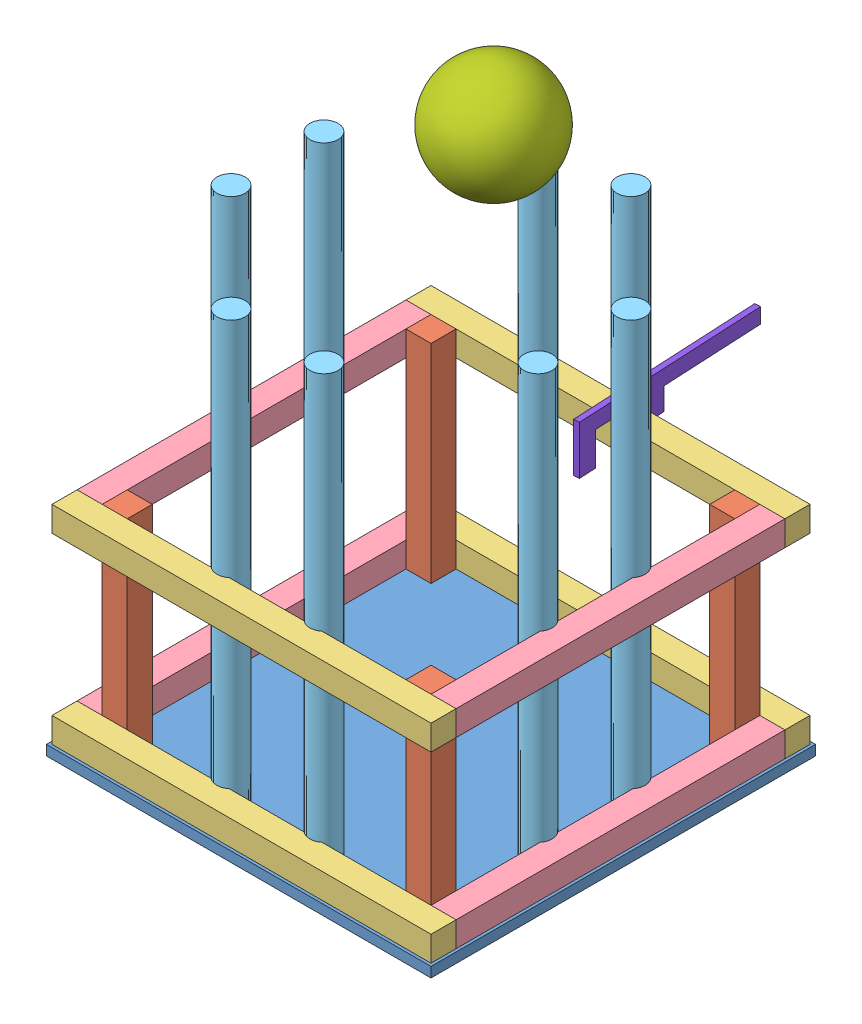
SolidWorks assembly cart, configuration Default. Lengths in mm.
Overall size (690 1266.2 920.66).
27 component instances, 8 part files, 1 mates.
Components (placement in the parent):
- cart plate-1: cart plate [Default] at (0 27 0) size (690 18 690)
- 4.5x4.5 l=40cm-1: 4.5x4.5 l=40cm [Default] at origin size (45 373 45)
- 4.5x4.5 l=40cm-2: 4.5x4.5 l=40cm [Default] x (0 0 -1) z (1 0 0) size (45 373 45)
- 4.5x4.5 l=40cm-3: 4.5x4.5 l=40cm [Default] x (-1 0 0) z (0 0 -1) size (45 373 45)
- 4.5x4.5 l=40cm-4: 4.5x4.5 l=40cm [Default] x (0 0 1) z (-1 0 0) size (45 373 45)
- 4.5x4.5 l=68cm-1: 4.5x4.5 l=68cm [Default] at origin size (680 45 45)
- 4.5x4.5 l=59cm-1: 4.5x4.5 l=59cm [Default] at origin size (45 45 590)
- 4.5x4.5 l=68cm-2: 4.5x4.5 l=68cm [Default] x (-1 0 0) z (0 0 -1) size (680 45 45)
- 4.5x4.5 l=59cm-2: 4.5x4.5 l=59cm [Default] x (-1 0 0) z (0 0 -1) size (45 45 590)
- 4.5x4.5 l=68cm-3: 4.5x4.5 l=68cm [Default] at (0 -328 0) size (680 45 45)
- 4.5x4.5 l=59cm-3: 4.5x4.5 l=59cm [Default] at (0 -328 0) size (45 45 590)
- 4.5x4.5 l=68cm-4: 4.5x4.5 l=68cm [Default] at (0 -328 0) x (-1 0 0) z (0 0 -1) size (680 45 45)
- 4.5x4.5 l=59cm-4: 4.5x4.5 l=59cm [Default] at (0 -328 0) x (-1 0 0) z (0 0 -1) size (45 45 590)
- pvc pipe l=80cm-1: pvc pipe l=80cm [Default] at origin size (50.8 773 50.8)
- pvc pipe l=80cm-2: pvc pipe l=80cm [Default] at (0 0 166.667) size (50.8 773 50.8)
- pvc pipe l=80cm-3: pvc pipe l=80cm [Default] x (0 0 -1) z (1 0 0) size (50.8 773 50.8)
- pvc pipe l=80cm-4: pvc pipe l=80cm [Default] at (166.667 0 0) x (0 0 -1) z (1 0 0) size (50.8 773 50.8)
- pvc pipe l=80cm-5: pvc pipe l=80cm [Default] x (-1 0 0) z (0 0 -1) size (50.8 773 50.8)
- pvc pipe l=80cm-6: pvc pipe l=80cm [Default] at (0 0 -166.667) x (-1 0 0) z (0 0 -1) size (50.8 773 50.8)
- pvc pipe l=80cm-7: pvc pipe l=80cm [Default] x (0 0 1) z (-1 0 0) size (50.8 773 50.8)
- pvc pipe l=80cm-8: pvc pipe l=80cm [Default] at (-166.667 0 0) x (0 0 1) z (-1 0 0) size (50.8 773 50.8)
- crazy wheel-1: crazy wheel [Default] at (185 27 -185) size (60 101 80)
- crazy wheel-2: crazy wheel [Default] at (185 27 185) size (60 101 80)
- crazy wheel-3: crazy wheel [Default] at (-185 27 -185) size (60 101 80)
- crazy wheel-4: crazy wheel [Default] at (-185 27 185) size (60 101 80)
- Ball-1: Ball [Default] at (140.5737 1092.1977 28.2994) size (200 200 200)
- F hand-1: F hand [Default] at (19.9991 445.2193 -490.7705) x (0.050393 0 0.998729) z (-0.998729 0 0.050393) size (342.75 87.22 10)
Mates (geometry in assembly coordinates):
- Coincident3: coincident anti-aligned: plane of 4.5x4.5 l=68cm-2 through (-295 418 -295) normal (0 1 0); plane of F hand-1 through (10.9437 418 -471.7963) normal (0 -1 0)
